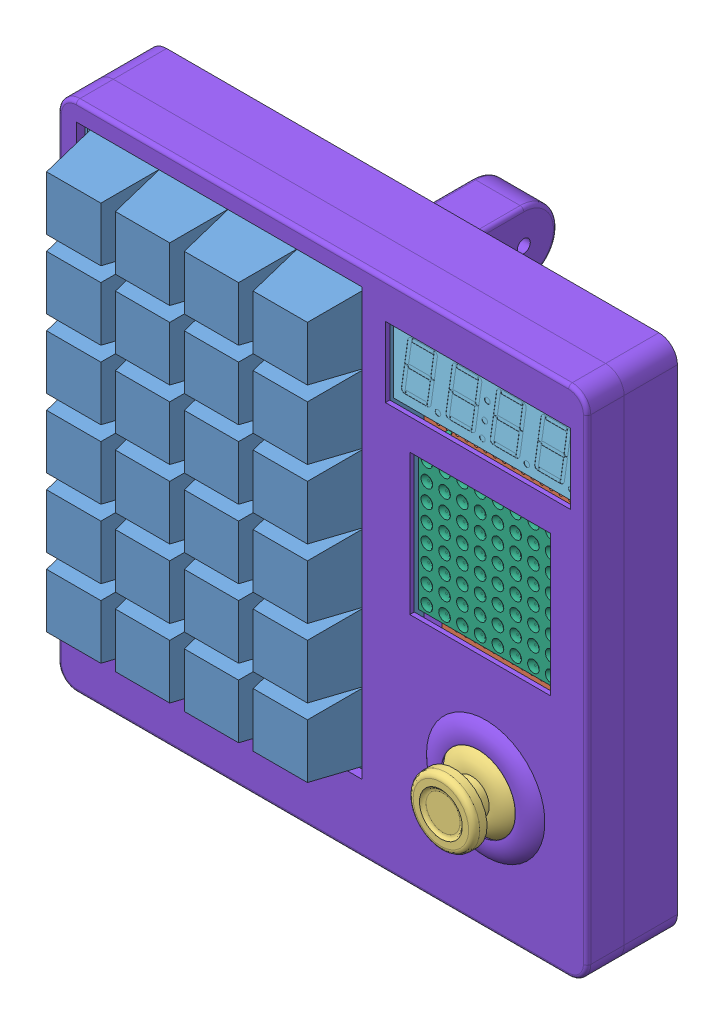
SolidWorks assembly keyPad, configuration  . Lengths in mm.
Overall size (143 138.6 68.5).
14 component instances, 8 part files, 11 mates.
Components (placement in the parent):
- KeyPad_6x4-1: KeyPad_6x4 [ ] at (21.2528 -121.2651 26.1764) size (80 132 27)
- JoystickModule-1: JoystickModule [ ] at (96.0184 -134.4159 26.4426) x (0 1 0) z (0 0 -1) size (70 51 36.5)
  - ProtoBoard_70x50-1: ProtoBoard_70x50 [ ] at (-45.8492 -29.7656 0.0662) size (70 51 1.2)
  - Joystick-1: Joystick [ ] at (-32.8035 -1.8618 -36.4338) x (-1 0 0) z (0 0 1) size (26.25 24.3 30.3)
  - connectors^JoystickModule-1: connectors^JoystickModule [По умолчанию] at (134.4159 -96.0184 26.4426) size (54.5 28.5 8) (virtual)
- LedModule-1: LedModule [ ] at (114.9979 -155.9956 21.8472) x (0 -1 0) z (0 0 1) size (70 51.1 21.4)
  - ProtoBoard_70x50-1: ProtoBoard_70x50 [ ] at (-91.7305 -48.7451 8.1292) size (70 51 1.2)
  - 7Seg_Led_5641BH-1: 7Seg_Led_5641BH [ ] at (-77.9305 -23.8451 9.5292) x (0 1 0) z (0 0 1) size (50 19 10.5)
  - Led_Matrix_1588BS-1: Led_Matrix_1588BS [Default] at (-41.1305 -23.2451 13.3292) x (0 -1 0) z (-1 0 0) size (38 12.5 38)
  - 2.54 pitch pin-1: 2.54 pitch pin [2] at (-27.3105 -1.7451 6.4192) x (-1 0 0) z (0 -1 0) size (2.54 13 5.08)
  - 2.54 pitch pin-2: 2.54 pitch pin [2] at (-27.3105 -42.3851 6.4192) x (-1 0 0) z (0 -1 0) size (2.54 13 5.08)
  - 2.54 pitch pin-3: 2.54 pitch pin [2] at (-47.6305 -1.7451 6.4192) x (-1 0 0) z (0 -1 0) size (2.54 13 5.08)
  - 2.54 pitch pin-4: 2.54 pitch pin [2] at (-47.6305 -42.3851 6.4192) x (-1 0 0) z (0 -1 0) size (2.54 13 5.08)
- keypad_Box-1: keypad_Box [ ] at (21.2528 -121.2651 39.1764) size (143 138.6 58.46)
Mates (geometry in assembly coordinates):
- Совпадение2: coincident: plane of KeyPad_6x4-1 through (-18.7472 -180.2651 39.1764) normal (0 -1 0); plane of JoystickModule-1/ProtoBoard_70x50-1 through (66.2528 -180.2651 25.1764) normal (0 -1 0)
- Расстояние1: distance = 5 mm: plane of JoystickModule-1/ProtoBoard_70x50-1 through (66.2528 -180.2651 25.1764) normal (-1 0 0); plane of KeyPad_6x4-1 through (61.2528 -62.2651 39.1764) normal (1 0 0)
- Расстояние4: distance = 6 mm: plane of JoystickModule-1/ProtoBoard_70x50-1 through (66.2528 -180.2651 25.1764) normal (0 0 -1); plane of LedModule-1/ProtoBoard_70x50-1 through (66.2528 -64.2651 31.1764) normal (0 0 1)
- Параллельность1: parallel: plane of JoystickModule-1/ProtoBoard_70x50-1 through (117.2528 -180.2651 25.1764) normal (1 0 0); plane of LedModule-1/ProtoBoard_70x50-1 through (117.2528 -64.2651 31.1764) normal (1 0 0)
- Совпадение4: coincident: plane of KeyPad_6x4-1 through (21.2528 -121.2651 39.1764) normal (0 0 1); plane of LedModule-1/Led_Matrix_1588BS-1 through (72.7528 -133.8651 39.1764) normal (0 0 1)
- На месте1: in place: plane of KeyPad_6x4-1 through (21.2528 -121.2651 39.1764) normal (0 0 1); plane of ? through (0 0 39.1764) normal (0 0 1); moOrthogonalPlaneRef_w of KeyPad_6x4-1 through (21.2528 -121.2651 39.1764) normal (0 0 1); plane of ? through (0 0 39.1764) normal (0 1 0); plane of KeyPad_6x4-1 through (21.2528 -121.2651 39.1764) normal (0 0 1); plane of ? through (0 0 39.1764) normal (1 0 0); plane of KeyPad_6x4-1 through (21.2528 -121.2651 39.1764) normal (0 0 1); unknown of keypad_Box-1
- Совпадение5: coincident: plane of KeyPad_6x4-1; plane of keypad_Box-1
- Совпадение6: coincident: moOrthogonalPlaneRef_w of KeyPad_6x4-1 through (21.2528 -121.2651 39.1764) normal (0 1 0); plane of keypad_Box-1 through (21.2528 -121.2651 39.1764) normal (0 1 0)
- Совпадение7: coincident: moOrthogonalPlaneRef_w of KeyPad_6x4-1 through (21.2528 -121.2651 39.1764) normal (-1 0 0); plane of keypad_Box-1 through (21.2528 -121.2651 39.1764) normal (1 0 0)
- Расстояние2: distance = 116 mm: plane of LedModule-1/ProtoBoard_70x50-1 through (66.2528 -64.2651 31.1764) normal (0 1 0); plane of JoystickModule-1/ProtoBoard_70x50-1 through (66.2528 -180.2651 25.1764) normal (0 -1 0)
- Совпадение5: coincident: plane of JoystickModule-1/ProtoBoard_70x50-1 through (66.2528 -180.2651 25.1764) normal (-1 0 0); plane of LedModule-1/ProtoBoard_70x50-1 through (66.2528 -64.2651 31.1764) normal (-1 0 0)
